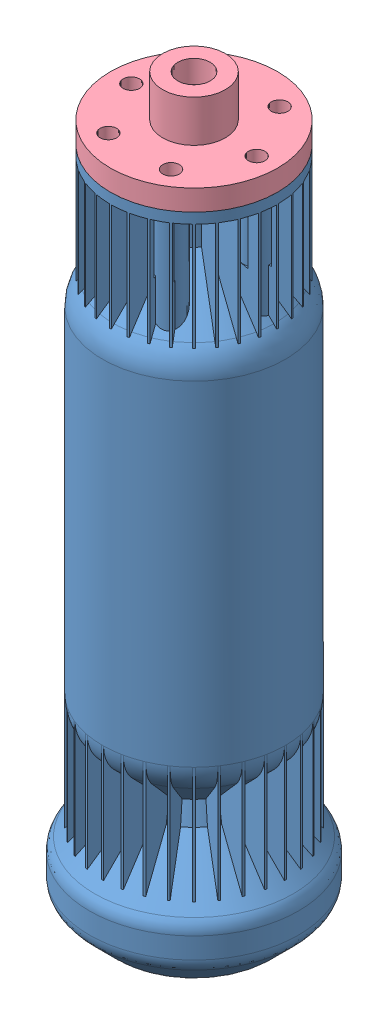
SolidWorks assembly regen additive faceshuttof pintle engine, configuration Default. Lengths in mm.
Overall size (130.67 465.93 128.57).
4 component instances, 4 part files, 7 mates.
Components (placement in the parent):
- slot cooling jacket 10-1: slot cooling jacket 10 [Default] at origin size (130.67 427.83 128.57)
- pintleSleeve-1: pintleSleeve [Default] at (0 66.6768 0) x (0.991028 0 -0.133656) z (0.133656 0 0.991028) size (20.32 53.72 20.32)
- pintle10-1: pintle10 [Default] at (0 85.6106 0) x (0.953019 0 0.302909) z (-0.302909 0 0.953019) size (38.1 82.55 38.1)
- pintle cap 10-1: pintle cap 10 [Default] at (0 85.6106 0) size (101.6 38.1 101.6)
Mates (geometry in assembly coordinates):
- Coincident1: coordinate: point of slot cooling jacket 10-1
- Concentric1: concentric anti-aligned: cylinder of slot cooling jacket 10-1 through (0 -277.9245 0) axis (0 -1 0) radius 10.16; cylinder of pintleSleeve-1 through (0 66.6768 0) axis (0 1 0) radius 10.16
- Concentric2: concentric aligned: cylinder of slot cooling jacket 10-1 through (0 -277.9245 0) axis (0 -1 0) radius 13.335; cylinder of pintle10-1 through (0 3.0606 0) axis (0 -1 0) radius 6.35
- Coincident2: coincident anti-aligned: plane of slot cooling jacket 10-1 through (-13.335 79.2606 0) normal (0 1 0); plane of pintle10-1 through (-13.4952 79.2606 -4.2893) normal (0 -1 0)
- Concentric3: concentric anti-aligned: cylinder of slot cooling jacket 10-1 through (0 -277.9245 0) axis (0 -1 0) radius 50.8; cylinder of pintle cap 10-1 through (0 123.7106 0) axis (0 1 0) radius 50.8
- Coincident3: coincident anti-aligned: plane of slot cooling jacket 10-1 through (-19.05 85.6106 0) normal (0 1 0); plane of pintle cap 10-1 through (-12.827 85.6106 0) normal (0 -1 0)
- Concentric4: concentric aligned: cylinder of slot cooling jacket 10-1 through (-38.1 85.6106 0) axis (0 1 0) radius 4.7625; cylinder of pintle cap 10-1 through (-38.1 98.3106 0) axis (0 1 0) radius 5.0419
